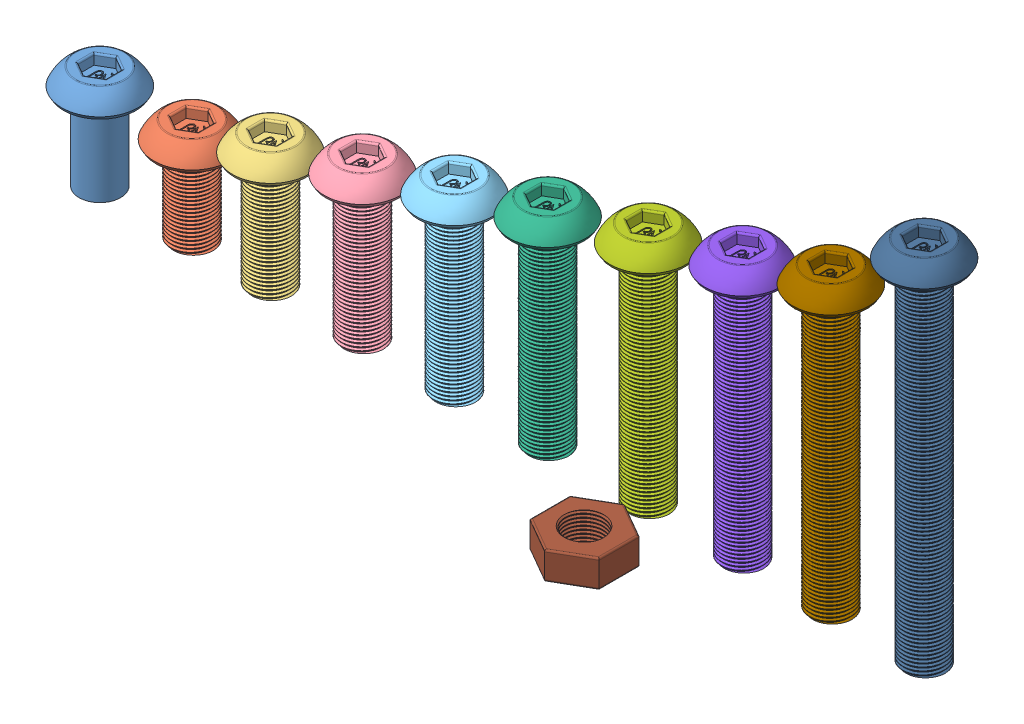
SolidWorks assembly Assem1, configuration Default. Lengths in mm.
Overall size (65.03 26.73 11.47).
11 component instances, 11 part files, 10 mates.
Components (placement in the parent):
- Screw_Machine_M3x-1: Screw_Machine_M3x [Default] at (-29.1315 0.8784 12.7959) size (5.5 7.5 5.5)
- Screw_Machine_M3x6-1: Screw_Machine_M3x6 [Default] at (-22.476 0.8784 12.7959) size (5.5 7.61 5.5)
- Screw_Machine_M3x8-1: Screw_Machine_M3x8 [Default] at (-16.8074 2.8784 12.7959) size (5.5 9.63 5.5)
- Screw_Machine_M3x10-1: Screw_Machine_M3x10 [Default] at (-10.1646 4.8784 12.7959) size (5.5 11.64 5.5)
- Screw_Machine_M3x12-1: Screw_Machine_M3x12 [Default] at (-3.5217 6.8784 12.7959) size (5.5 13.65 5.5)
- Screw_Machine_M3x14-1: Screw_Machine_M3x14 [Default] at (3.2097 8.8784 12.7967) size (5.5 15.66 5.5)
- Screw_Machine_M3x16-1: Screw_Machine_M3x16 [Default] at (10.4725 10.8784 12.7959) size (5.5 17.67 5.5)
- Screw_Machine_M3x18-1: Screw_Machine_M3x18 [Default] at (17.2925 12.8784 12.7922) size (5.5 19.69 5.5)
- Screw_Machine_M3x20-1: Screw_Machine_M3x20 [Default] at (23.6696 14.8784 12.7918) size (5.5 21.7 5.5)
- Screw_Machine_M3x25-1: Screw_Machine_M3x25 [Default] at (30.4011 19.8784 12.7902) size (5.5 26.73 5.5)
- Nut_Machine_M3x2-1: Nut_Machine_M3x2 [Default] at (11.7065 -5.1216 18.6243) size (5 2.18 5.77)
Mates (geometry in assembly coordinates):
- Coincident1: coincident aligned: plane of Screw_Machine_M3x20-1 through (23.6696 -5.1216 14.2918) normal (0 -1 0); plane of Screw_Machine_M3x25-1 through (30.4011 -5.1216 14.2902) normal (0 -1 0)
- Coincident2: coincident aligned: plane of Screw_Machine_M3x18-1 through (17.2925 -5.1216 14.2922) normal (0 -1 0); plane of Screw_Machine_M3x20-1 through (23.6696 -5.1216 14.2918) normal (0 -1 0)
- Coincident3: coincident aligned: plane of Screw_Machine_M3x16-1 through (10.4725 -5.1216 14.2959) normal (0 -1 0); plane of Screw_Machine_M3x18-1 through (17.2925 -5.1216 14.2922) normal (0 -1 0)
- Coincident4: coincident aligned: plane of Screw_Machine_M3x14-1 through (3.2097 -5.1216 14.2967) normal (0 -1 0); plane of Screw_Machine_M3x16-1 through (10.4725 -5.1216 14.2959) normal (0 -1 0)
- Coincident5: coincident aligned: plane of Screw_Machine_M3x12-1 through (-3.5217 -5.1216 14.2959) normal (0 -1 0); plane of Screw_Machine_M3x14-1 through (3.2097 -5.1216 14.2967) normal (0 -1 0)
- Coincident6: coincident aligned: plane of Screw_Machine_M3x10-1 through (-10.1646 -5.1216 14.2959) normal (0 -1 0); plane of Screw_Machine_M3x12-1 through (-3.5217 -5.1216 14.2959) normal (0 -1 0)
- Coincident7: coincident aligned: plane of Screw_Machine_M3x8-1 through (-16.8074 -5.1216 14.2959) normal (0 -1 0); plane of Screw_Machine_M3x10-1 through (-10.1646 -5.1216 14.2959) normal (0 -1 0)
- Coincident8: coincident aligned: plane of Screw_Machine_M3x6-1 through (-22.476 -5.1216 14.2959) normal (0 -1 0); plane of Screw_Machine_M3x8-1 through (-16.8074 -5.1216 14.2959) normal (0 -1 0)
- Coincident9: coincident aligned: plane of Screw_Machine_M3x-1 through (-29.1315 -5.1216 14.2959) normal (0 -1 0); plane of Screw_Machine_M3x6-1 through (-22.476 -5.1216 14.2959) normal (0 -1 0)
- Coincident10: coincident aligned: plane of Screw_Machine_M3x25-1 through (30.4011 -5.1216 14.2902) normal (0 -1 0); plane of Nut_Machine_M3x2-1 through (11.7065 -5.1216 18.6243) normal (0 -1 0)
